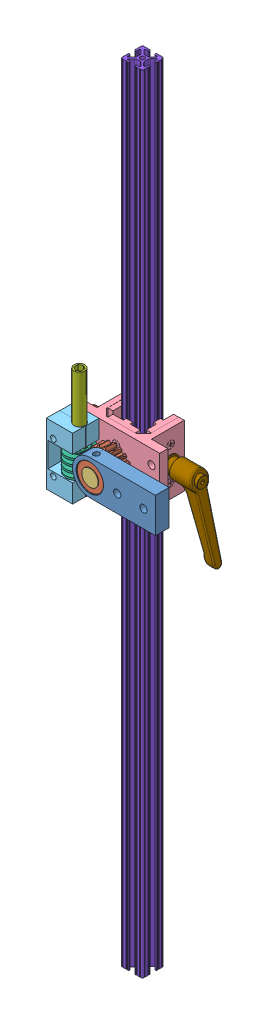
SolidWorks assembly Assembly_main_body_1.png, configuration Default. Lengths in mm.
Overall size (176.2 914.4 90.37).
12 component instances, 10 part files, 0 mates.
Components (placement in the parent):
- ATM_part2-1: ATM_part2 [Default] at (42.817 58.4844 64.8947) size (96.45 40.64 15.9)
- Part2^Assembly_main_body_1-1: Part2^Assembly_main_body_1 [Default] at origin (virtual)
- 57545K511_SPEED-REDUCING WORM GEAR FOR 90 DEG TRANSFER-1: 57545K511_SPEED-REDUCING WORM GEAR FOR 90 DEG TRANSFER [57545K511] at (4.737 58.6317 58.1053) x (0 1 0) z (1 0 0) size (44.78 28.61 44.18)
- ATM_part1-3: ATM_part1 [Default] at (4.8915 58.5282 80.9531) x (0 1 0) z (-1 0 0) size (19.05 29.84 19.05)
- 47065T962_ALUMINUM T-SLOTTED FRAMING EXTRUSION-1: 47065T962_ALUMINUM T-SLOTTED FRAMING EXTRUSION [47065T962] at (5.088 57.9029 3.2128) x (1 0 0) z (0 -1 0) size (101.6 47.62 71.42)
- ATM_worm_caseR-1: ATM_worm_caseR [Default] at (-45.0925 58.0152 66.2025) x (0 1 0) z (0 0 -1) size (71.44 30.48 15.24)
- 57545K527_SPEED-REDUCING WORM GEAR FOR 90 DEG TRANSFER (1)-1: 57545K527_SPEED-REDUCING WORM GEAR FOR 90 DEG TRANSFER (1) [57545K527] at (-21.7583 57.6898 66.6468) x (0 0 1) z (0 1 0) size (31.13 29.72 30.93)
- ATM_worm_shaft-1: ATM_worm_shaft [Default] at (-21.425 22.0769 66.847) x (0 0 -1) z (0 1 0) size (12.65 13.45 127)
- ATM_worm_caseR-2: ATM_worm_caseR [Default] at (-45.1021 58.2563 66.3541) x (0 -1 0) z (0 0 1) size (71.44 30.48 15.24)
- 47065T412_ALUMINUM T-SLOTTED FRAMING EXTRUSION-1: 47065T412_ALUMINUM T-SLOTTED FRAMING EXTRUSION [47065T412] at (4.8252 -6.4827 19.858) x (0 0 -1) z (0 1 0) size (25.4 25.4 914.4)
- 60585K320_LINEAR BEARING FOR T-SLOTTED FRAMING-1: 60585K320_LINEAR BEARING FOR T-SLOTTED FRAMING [60585K32] at (45.6882 57.3486 18.8633) size (75.81 88.77 38.39)
- 60585K320_LINEAR BEARING FOR T-SLOTTED FRAMING-3: 60585K320_LINEAR BEARING FOR T-SLOTTED FRAMING [60585K32] at (-35.8444 58.0912 18.817) x (-1 0 0) z (0 0 -1) size (75.81 88.77 38.39)
